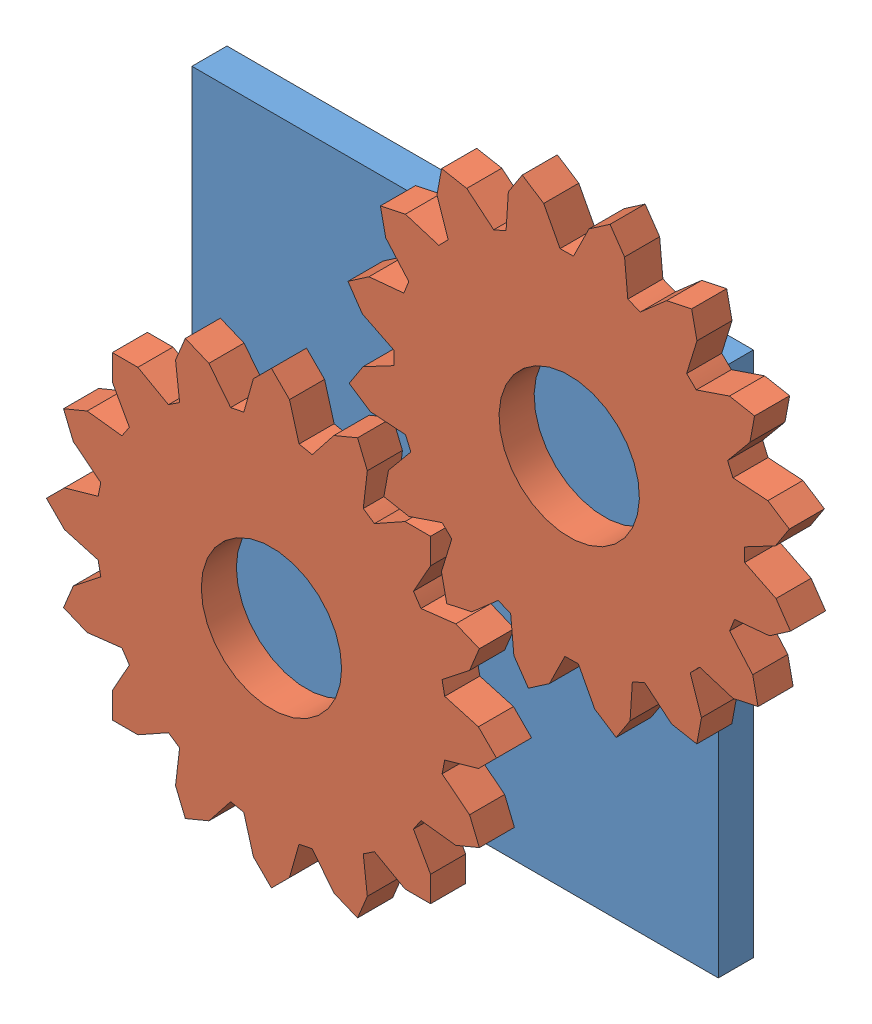
SolidWorks assembly gears_connected, configuration Default. Lengths in mm.
Overall size (238.16 238.16 20).
3 component instances, 2 part files, 4 mates.
Components (placement in the parent):
- plane-2: plane [Default] at origin size (150 150 10)
- gear1-1: gear1 [Default] at (-42.5146 -42.3381 10) size (128.25 128.25 10)
- gear1-2: gear1 [Default] at (42.3381 42.5146 10) x (0.823696 0.567031 0) z (0 0 1) size (128.25 128.25 10)
Mates (geometry in assembly coordinates):
- Coincident1: coincident anti-aligned: plane of plane-2 through (0 0 10) normal (0 0 1); plane of gear1-1 through (-42.5146 -42.3381 10) normal (0 0 -1)
- Coincident2: coincident anti-aligned: plane of plane-2 through (0 0 10) normal (0 0 1); plane of gear1-2 through (42.3381 42.5146 10) normal (0 0 -1)
- Concentric1: concentric anti-aligned: circle of gear1-1
- Concentric2: concentric anti-aligned: circle of gear1-2
